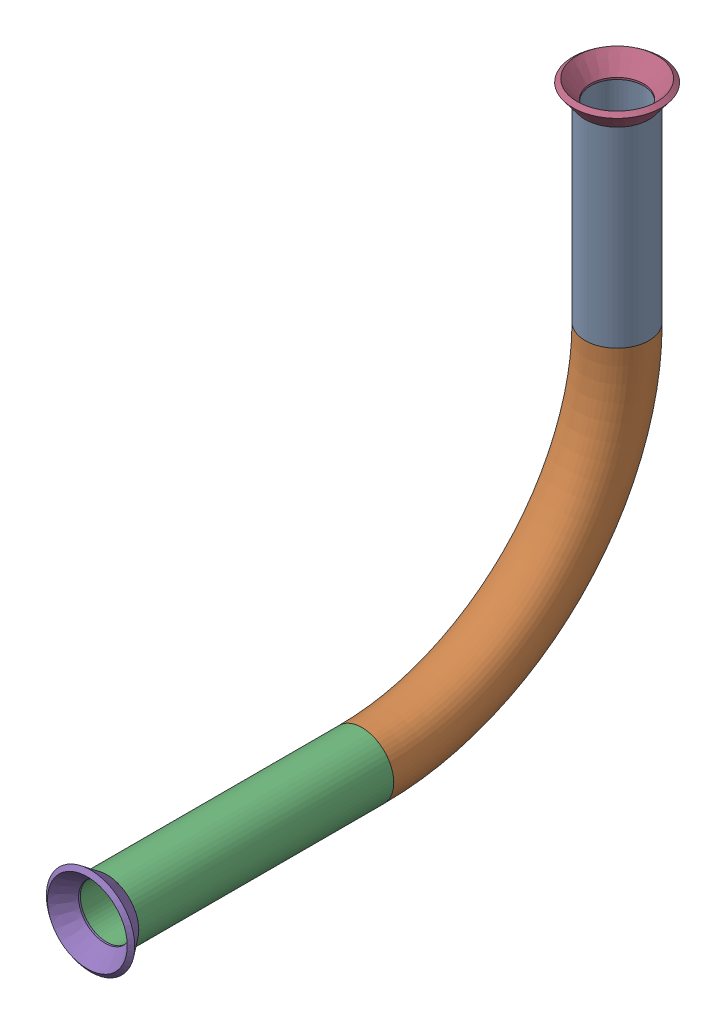
SolidWorks assembly Pipe 38, configuration Default. Lengths in mm.
Overall size (17.59 101.58 114.23).
3 component instances, 2 part files, 4 mates.
Components (placement in the parent):
- Part1-1: Part1 [Default<As Machined>] at origin size (12.7 95.25 107.9)
- Flared pipe end - .5 inch-1: Flared pipe end - .5 inch [Default<As Machined>] at (0 -187.6805 259.1796) x (1 0 0.00017) z (0 1 0) size (17.59 17.59 3.89)
- Flared pipe end - .5 inch-2: Flared pipe end - .5 inch [Default<As Machined>] at (0 -276.5805 360.7276) x (1 -0.00017 0) z (0 0 1) size (17.59 17.59 3.89)
Mates (geometry in assembly coordinates):
- Coincident1032: coincident: plane of Part1-1 through (0 -187.6805 259.1796) normal (0 1 0); plane of Flared pipe end - .5 inch-1 through (0.0009 -187.6805 253.8964) normal (0 -1 0)
- Concentric658: concentric: circle of Part1-1; circle of Flared pipe end - .5 inch-1
- Coincident1033: coincident: plane of Part1-1 through (0 -276.5805 360.7276) normal (0 0 1); plane of Flared pipe end - .5 inch-2 through (0.0009 -271.2973 360.7276) normal (0 0 -1)
- Concentric659: concentric: circle of Part1-1; circle of Flared pipe end - .5 inch-2
